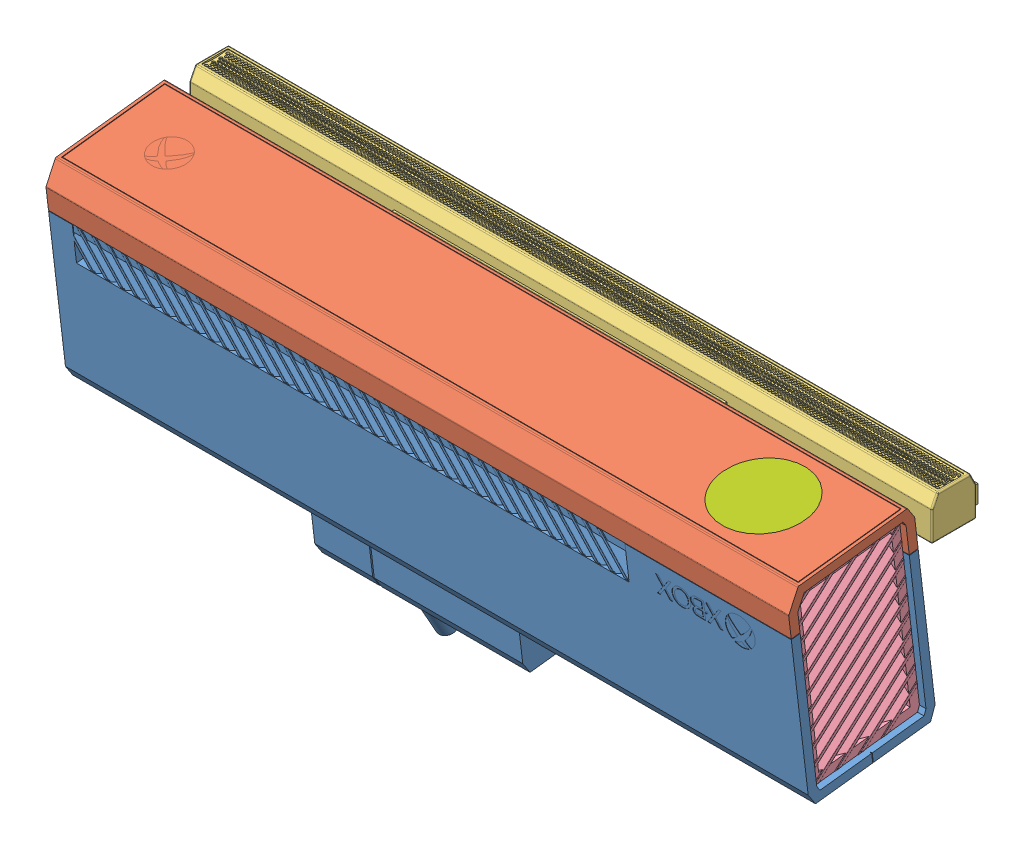
SolidWorks assembly AS1, configuration Default. Lengths in mm.
Overall size (250 121.83 65.49).
8 component instances, 8 part files, 19 mates.
Components (placement in the parent):
- 1-1: 1 [Default] at (-125 41.8074 21.2837) x (0 0.993094 0.117321) z (1 0 0) size (114.6 50.3 250)
- 2-1: 2 [Default] at (-125 28.1027 19.6646) x (0 0.993094 0.117321) z (1 0 0) size (13.8 43 250)
- 3-1: 3 [Default] at origin size (250 82 32.5)
- 4-1: 4 [Default] at (120 -21.7062 17.6613) x (0 0.993094 0.117321) z (1 0 0) size (60.5 37 3)
- 5-1: 5 [Default] at (-120 -21.7062 17.6613) x (0 0.993094 0.117321) z (1 0 0) size (60.5 37 3)
- 6-1: 6 [Default] at (0 -32.2685 30.3556) x (1 0 0) z (0 -0.993094 -0.117321) size (44 36 8)
- 7-1: 7 [Default] at (95 36.4213 41.3048) x (-1 0 0) z (0 0.993094 0.117321) size (28 28 3)
- 8-1: 8 [Default] at (95 31.9524 40.7769) x (-1 0 0) z (0 0.993094 0.117321) size (12 12 4)
Mates (geometry in assembly coordinates):
- Coincident3: coincident anti-aligned: plane of 1-1 through (-125.0001 29.8162 60.1452) normal (0 -0.117321 0.993094); plane of 2-1 through (125 29.8162 60.1452) normal (0 0.117321 -0.993094)
- Coincident4: coincident aligned: plane of 1-1 through (125 41.8074 21.2837) normal (1 0 0); plane of 2-1 through (125 28.1027 19.6646) normal (1 0 0)
- Coincident5: coincident aligned: plane of 1-1 through (125 41.8074 21.2837) normal (1 0 0); plane of 3-1 through (125 0 5) normal (1 0 0)
- Concentric1: concentric aligned: cylinder of 1-1 through (67 30.5 27.5) axis (-1 0 0) radius 2.5; cylinder of 3-1 through (0 30.5 27.5) axis (-1 0 0) radius 3.5
- Coincident6: coincident anti-aligned: plane of 1-1 through (120 41.8074 21.2837) normal (1 0 0); plane of 4-1 through (120 -21.7062 17.6613) normal (-1 0 0)
- Coincident8: coincident anti-aligned: plane of 1-1 through (120 36.7797 23.7106) normal (0 -0.117321 0.993094); plane of 4-1 through (122.8 27.5521 22.6205) normal (0 0.117321 -0.993094)
- Coincident9: coincident anti-aligned: plane of 1-1 through (-120 41.8074 21.2837) normal (-1 0 0); plane of 5-1 through (-120 -21.7062 17.6613) normal (1 0 0)
- Coincident10: coincident anti-aligned: plane of 1-1 through (-120 -25.8467 52.7093) normal (0 0.993094 0.117321); plane of 5-1 through (-122.8 -25.8467 52.7093) normal (0 -0.993094 -0.117321)
- Coincident11: coincident anti-aligned: plane of 1-1 through (-120 23.2112 59.3649) normal (0 0.117321 -0.993094); plane of 5-1 through (-122.8 23.2112 59.3649) normal (0 -0.117321 0.993094)
- Coincident12: coincident anti-aligned: plane of 1-1 through (-125 -30.1919 12.7779) normal (0 -0.993094 -0.117321); plane of 6-1 through (0 -32.2685 30.3556) normal (0 0.993094 0.117321)
- Coincident13: coincident anti-aligned: plane of 1-1 through (22 -30.1567 12.48) normal (-1 0 0); plane of 6-1 through (22 -38.1015 11.5414) normal (1 0 0)
- Coincident14: coincident anti-aligned: plane of 1-1 through (22 -34.3803 48.2313) normal (0 0.117321 -0.993094); plane of 6-1 through (22 -42.325 47.2928) normal (0 -0.117321 0.993094)
- Coincident16: coincident anti-aligned: plane of 1-1 through (-125.0001 38.3759 24.7592) normal (0 0.993094 0.117321); plane of 2-1 through (125 38.3759 24.7592) normal (0 -0.993094 -0.117321)
- Concentric2: concentric anti-aligned: cylinder of 2-1 through (95 25.6959 40.0378) axis (0 0.993094 0.117321) radius 14; cylinder of 7-1 through (95 39.4006 41.6568) axis (0 -0.993094 -0.117321) radius 14
- Coincident17: coincident aligned: plane of 2-1 through (125 41.5728 23.2699) normal (0 0.993094 0.117321); plane of 7-1 through (95 39.4006 41.6568) normal (0 0.993094 0.117321)
- Concentric3: concentric anti-aligned: cylinder of 1-1 through (95 31.9524 40.7769) axis (0 0.993094 0.117321) radius 6; cylinder of 8-1 through (95 33.9386 41.0115) axis (0 -0.993094 -0.117321) radius 6
- Coincident18: coincident anti-aligned: plane of 1-1 through (95 31.9524 40.7769) normal (0 0.993094 0.117321); plane of 8-1 through (95 31.9524 40.7769) normal (0 -0.993094 -0.117321)
- Coincident19: coordinate: point of 3-1; point of assembly
- Coincident20: coincident anti-aligned: plane of 2-1 through (125 38.3759 24.7592) normal (0 -0.993094 -0.117321); plane of 4-1 through (122.8 38.3759 24.7592) normal (0 0.993094 0.117321)
